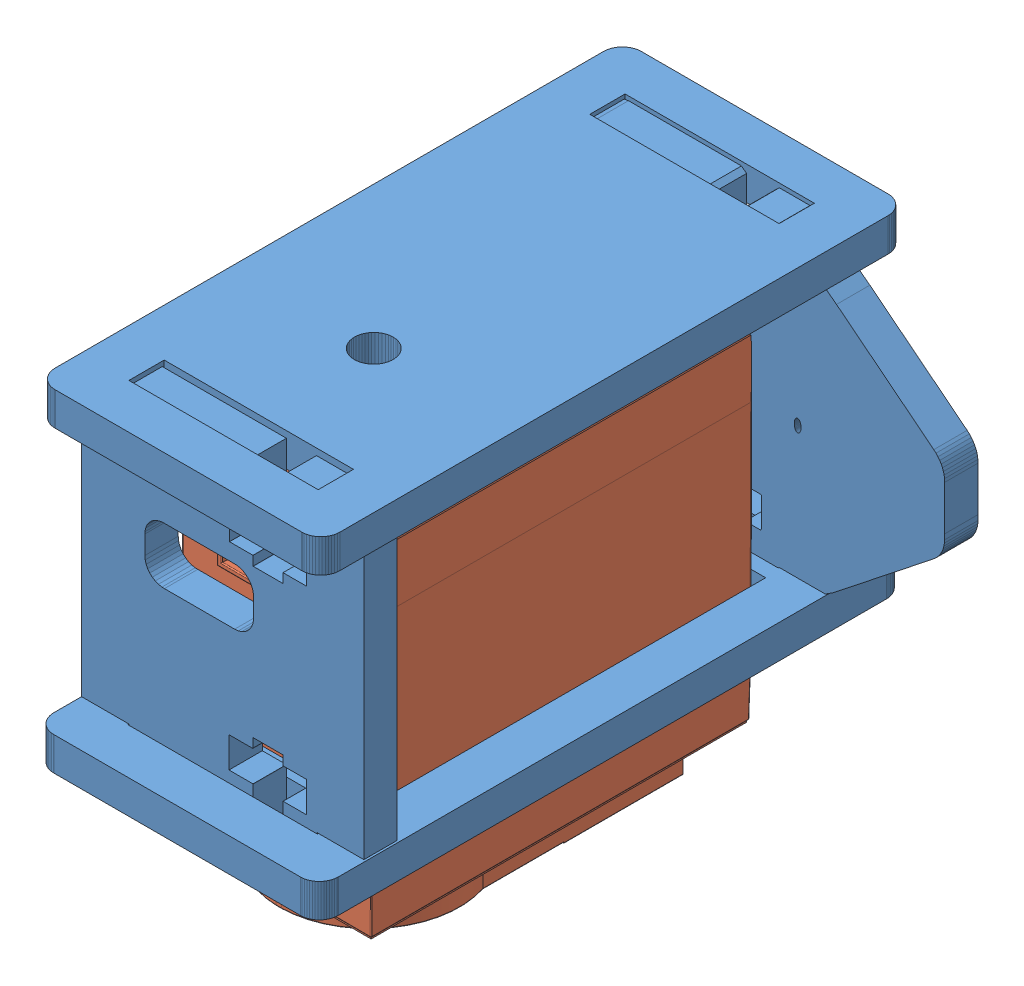
SolidWorks assembly right_shoulder_upper_arm_clamp, configuration Default. Lengths in mm.
Overall size (55.01 47.39 61.58).
4 component instances, 3 part files, 2 mates.
Components (placement in the parent):
- right_shoulder_upper_arm_clamp_100-1: right_shoulder_upper_arm_clamp_100 [Default] at (-29.8099 10.0805 38.173) size (55.01 34.84 61.58)
- main_assembly-1: main_assembly [Default] at (-17.4802 68.5784 30.0701) x (0.999997 -0.002447 0) z (-0.002447 -0.999997 0) size (20 53 41.5)
  - main_body-1: main_body [Default] at (15.1003 34.2066 38.7045) size (20 53 41.5)
- hs-422_horn_2wings_sws-1: hs-422_horn_2wings_sws [Default] at (-2.5608 27.2192 36.0348) x (-0.002403 0.999997 0) z (0.999997 0.002403 0) size (9.1 5 34)
Mates (geometry in assembly coordinates):
- Coincident1: coincident anti-aligned: line of right_shoulder_upper_arm_clamp_100-1 through (-12.5236 9.8616 43.2202) axis (0 0 1); line of main_assembly-1/main_body-1 through (-12.5236 9.8616 84.0266) axis (0 0 -1)
- Concentric2: concentric aligned: circle of right_shoulder_upper_arm_clamp_100-1; circle of hs-422_horn_2wings_sws-1
